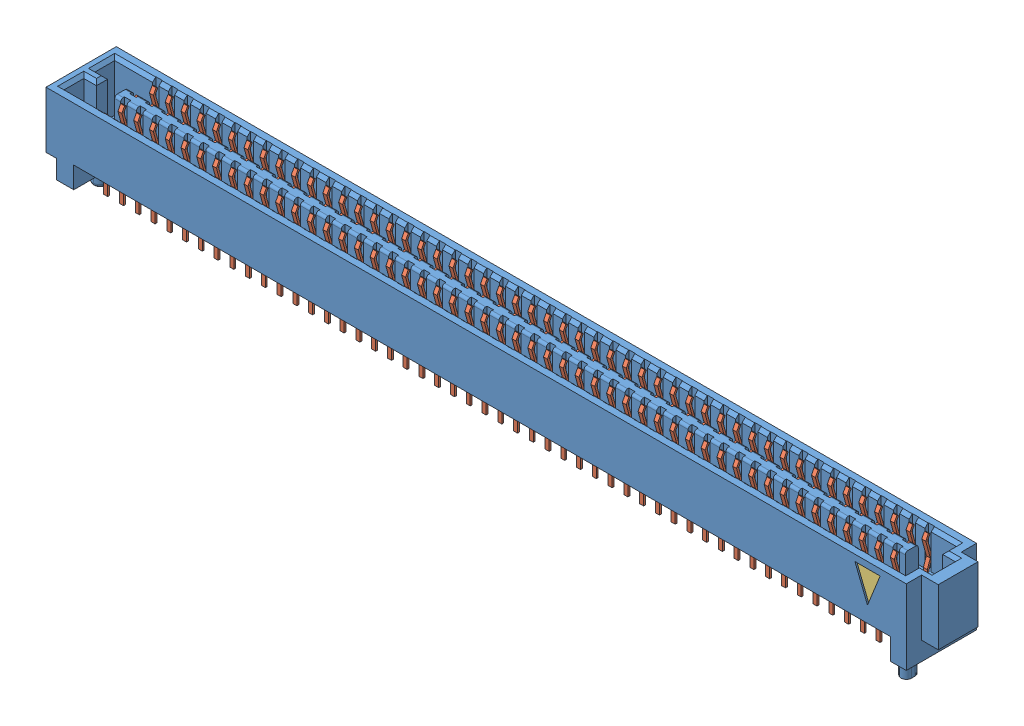
SolidWorks assembly SEAF_50_06_0_L_04_2_A_K_TR, configuration Default. Lengths in mm.
Overall size (70.66 7.32 5.66).
4 component instances, 4 part files, 0 mates.
Components (placement in the parent):
- _SEAF_50_06_0_L_04_1_A_0_K_TR_BODY_2_2-1: _SEAF_50_06_0_L_04_1_A_0_K_TR_BODY_2_2 [Default] at origin size (70.66 7.32 5.66)
- _SEAF_50_06_0_L_04_1_A_0_K_TR_cCON2_4-1: _SEAF_50_06_0_L_04_1_A_0_K_TR_cCON2_4 [Default] at origin size (62.55 5.65 5.41)
- _SEAF_04_K_PAD_6-1: _SEAF_04_K_PAD_6 [Default] at (-0.2286 4.318 0) size (6.5 0.13 6.5) (hidden)
- _SEAF_TRIANGLE_FIRST_PIN_8-1: _SEAF_TRIANGLE_FIRST_PIN_8 [Default] at (30.861 0.762 2.5781) size (2.03 2.54 0.13)
